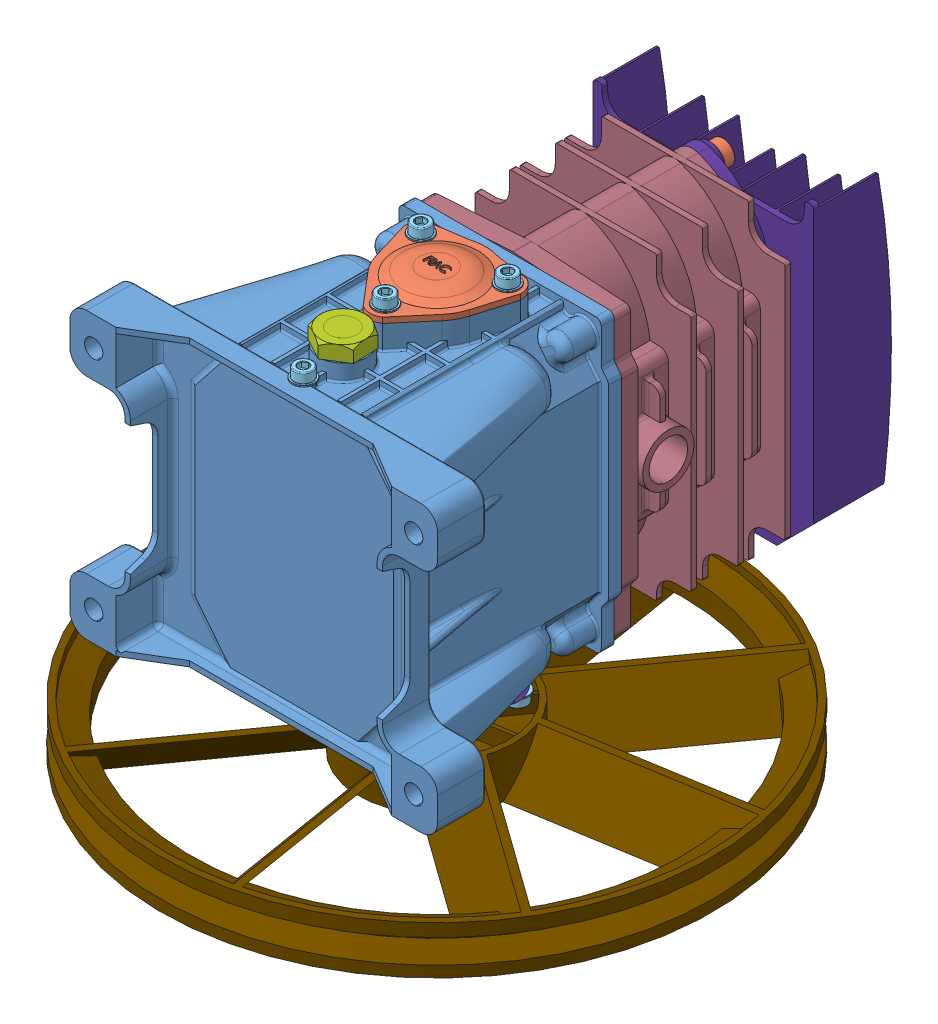
SolidWorks assembly ASSIEME, configuration Default. Lengths in mm.
Overall size (344.78 250.04 359.67).
63 component instances, 27 part files, 88 mates.
Components (placement in the parent):
- carter-1: carter [Default] at (-13.0886 -2.2266 200) size (200 182 141)
- COPERCHIO_6203-1: COPERCHIO_6203 [Default] at (-13.0886 84.7734 200) x (1 0 0) z (0 1 0) size (63.63 62.78 24)
- SKF_6203-1: SKF_6203 [Default] at (-13.0886 80.7734 123.5) x (0 -1 0) z (-0.202548 0 -0.979272) size (12 40 40)
  - SKF_6203_12-1: SKF_6203_12 [Default] x (1 0 0) z (0 -0.707107 0.707107) size (6.75 6.75 6.75)
  - SKF_6203_12-2: SKF_6203_12 [Default] x (1 0 0) z (0 -1 0) size (6.75 6.75 6.75)
  - SKF_6203_12-3: SKF_6203_12 [Default] x (1 0 0) z (0 -0.707107 -0.707107) size (6.75 6.75 6.75)
  - SKF_6203_12-4: SKF_6203_12 [Default] x (1 0 0) z (0 0 -1) size (6.75 6.75 6.75)
  - SKF_6203_12-5: SKF_6203_12 [Default] x (1 0 0) z (0 0.707107 -0.707107) size (6.75 6.75 6.75)
  - SKF_6203_12-6: SKF_6203_12 [Default] x (1 0 0) z (0 1 0) size (6.75 6.75 6.75)
  - SKF_6203_12-7: SKF_6203_12 [Default] x (1 0 0) z (0 0.707107 0.707107) size (6.75 6.75 6.75)
  - SKF_6203_12-8: SKF_6203_12 [Default] at origin size (6.75 6.75 6.75)
  - SKF_6203_21-1: SKF_6203_21 [Default] at origin size (12 40 40)
  - SKF_6203_23-1: SKF_6203_23 [Default] at origin size (12 24.5 24.5)
- albero (2)-2: albero (2) [Default] at (-13.0886 -75.1766 123.5) x (-0.16255 0 -0.9867) z (0 -1 0) size (47.4 88.29 224.6)
- boccola-1: boccola [Default] at (-13.0886 67.7734 123.5) x (-0.874312 0 0.485365) z (0 1 0) size (21 21 1)
- COPERCHIO_6204-1: COPERCHIO_6204 [Default] at (-15.8848 -102.2266 135.5048) x (-1 0 0) z (0 1 0) size (66.44 64.43 29)
- SKF_6204-1: SKF_6204 [Default] at (-13.0886 -89.1766 123.5) x (0 1 0) z (-0.972829 0 0.231526) size (14 47 47)
  - SKF_6204_12-1: SKF_6204_12 [Default] x (1 0 0) z (0 -0.707107 0.707107) size (7.94 7.94 7.94)
  - SKF_6204_12-2: SKF_6204_12 [Default] x (1 0 0) z (0 -1 0) size (7.94 7.94 7.94)
  - SKF_6204_12-3: SKF_6204_12 [Default] x (1 0 0) z (0 -0.707107 -0.707107) size (7.94 7.94 7.94)
  - SKF_6204_12-4: SKF_6204_12 [Default] x (1 0 0) z (0 0 -1) size (7.94 7.94 7.94)
  - SKF_6204_12-5: SKF_6204_12 [Default] x (1 0 0) z (0 0.707107 -0.707107) size (7.94 7.94 7.94)
  - SKF_6204_12-6: SKF_6204_12 [Default] x (1 0 0) z (0 1 0) size (7.94 7.94 7.94)
  - SKF_6204_12-7: SKF_6204_12 [Default] x (1 0 0) z (0 0.707107 0.707107) size (7.94 7.94 7.94)
  - SKF_6204_12-8: SKF_6204_12 [Default] at origin size (7.94 7.94 7.94)
  - SKF_6204_21-1: SKF_6204_21 [Default] at origin size (14 47 47)
  - SKF_6204_23-1: SKF_6204_23 [Default] at origin size (14 28.8 28.8)
- SKF_20X47X7_CRW1_R-1: SKF_20X47X7_CRW1_R [Default] at (-13.0886 -97.2266 123.5) x (0 1 0) z (0.036674 0 -0.999327) size (7 47 47)
- cilindro-1: cilindro [Default] at (-13.0886 -2.2266 82) x (0 1 0) z (0 0 1) size (170 120 97.5)
- biella (1)-1: biella (1) [Default] at (-33.8093 30.3234 126.9135) x (-0.243773 0 0.969832) z (0 1 0) size (142 47 15.03)
- biella (1)-2: biella (1) [Default] at (7.6321 -34.6766 120.0865) x (0.243773 0 0.969832) z (0 1 0) size (142 47 15.03)
- spinotto-1: spinotto [Default] at (-13.0886 53.5234 44.4778) x (0.997872 0 0.065206) z (0 -1 0) size (13 13 46.5)
- spinotto-2: spinotto [Default] at (-13.0886 -11.4766 37.6507) x (0.995135 0 0.098522) z (0 -1 0) size (13 13 46.5)
- Pistone_Compressore (1)-1: Pistone_Compressore (1) [Default] at (-13.0886 30.2734 66.4778) x (0 0 -1) z (0 -1 0) size (47 53 53)
- Pistone_Compressore (1)-2: Pistone_Compressore (1) [Default] at (-13.0886 -34.7266 59.6507) x (0 0 -1) z (0 -1 0) size (47 53 53)
- testata-1: testata [Default] at (-13.0886 -2.2266 -21.5) x (0 -1 0) z (0 0 1) size (170 120 48.28)
- puleggia2-1: puleggia2 [Default] at (-161.0937 -111.4306 147.8824) x (0 -1 0) z (-0.16255 0 -0.9867) size (36.2 300 300)
- chiavetta-1: chiavetta [Default] at (-0.5703 -123.1766 119.5121) x (-0.041845 -0.9991 0.006894) z (0.16255 0 0.9867) size (15.94 7.3 3.9)
- Bulloni a brugola M8x35mm-1: Bulloni a brugola M8x35mm [Default] at (-13.0886 67.7734 10.5) x (0.984599 -0.17483 0) z (0 0 -1) size (16 16 43.35)
- Bulloni a brugola M8x45mm-1: Bulloni a brugola M8x45mm [Default] at (-50.5886 26.2734 7.5) x (-0.918061 -0.396439 0) z (0 0 -1) size (16 16 53.35)
- Bulloni a brugola M8x45mm-2: Bulloni a brugola M8x45mm [Default] at (24.4114 26.2734 20.5) x (-0.229828 0.973231 0) z (0 0 -1) size (16 16 53.35)
- Bulloni a brugola M8x45mm-3: Bulloni a brugola M8x45mm [Default] at (24.4114 -30.7266 20.5) x (-0.229828 0.973231 0) z (0 0 -1) size (16 16 53.35)
- Bulloni a brugola M8x45mm-4: Bulloni a brugola M8x45mm [Default] at (-13.0886 -72.2266 7.5) x (-0.461564 -0.887107 0) z (0 0 -1) size (16 16 53.35)
- Bulloni a brugola M8x45mm-5: Bulloni a brugola M8x45mm [Default] at (-50.5886 -30.7266 7.5) x (-0.618825 0.785529 0) z (0 0 -1) size (16 16 53.35)
- Bulloni a brugola M8x15-1: Bulloni a brugola M8x15 [Default] at (-13.0886 -127.6306 123.5) x (0.472726 0 0.88121) z (0 -1 0) size (24 24 28.35)
- Bulloni a brugola M6x6mm-1: Bulloni a brugola M6x6mm [Default] at (-13.0886 73.7734 151.5) x (0.218907 0 0.975746) z (0 1 0) size (12 12 20.29)
- Bulloni a brugola M6x6mm-2: Bulloni a brugola M6x6mm [Default] at (-36.7318 73.7734 108.5) x (-1 0 0) z (0 1 0) size (12 12 20.29)
- Bulloni a brugola M6x6mm-3: Bulloni a brugola M6x6mm [Default] at (10.5546 73.7734 108.5) x (-1 0 0) z (0 1 0) size (12 12 20.29)
- Bulloni a brugola M6x6mm-7: Bulloni a brugola M6x6mm [Default] at (14.0223 -88.2266 106.5) x (0 0 1) z (0 -1 0) size (12 12 20.29)
- Bulloni a brugola M6x6mm-8: Bulloni a brugola M6x6mm [Default] at (-40.1995 -88.2266 106.5) x (0 0 1) z (0 -1 0) size (12 12 20.29)
- Bulloni a brugola M6x6mm-9: Bulloni a brugola M6x6mm [Default] at (-13.0886 -88.2266 155.5) x (0 0 1) z (0 -1 0) size (12 12 20.29)
- Bulloni a brugola M6x6mm-11: Bulloni a brugola M6x6mm [Default] at (-13.0886 61.2734 196) x (0 0 -1) z (0 1 0) size (12 12 20.29)
- 7941013-2: 7941013 [Default] at (-13.0886 54.5234 44.4778) x (0 -1 0) z (0 0 1) size (1 13.87 14.1)
- 7941013-3: 7941013 [Default] at (-13.0886 7.0234 44.4778) x (0 -1 0) z (0 0 1) size (1 13.87 14.1)
- 7941013-4: 7941013 [Default] at (-13.0886 -11.4766 37.6507) x (0 1 0) z (0 0 1) size (1 13.87 14.1)
- 7941013-5: 7941013 [Default] at (-13.0886 -58.9766 37.6507) x (0 1 0) z (0 0 1) size (1 13.87 14.1)
- tappo livello olio-1: tappo livello olio [Default] at (-13.0886 67.7734 174.5) x (-0.88085 0 -0.473395) z (0 1 0) size (27.71 24 21)
- segmento1-1: segmento1 [Default] at (-13.0886 30.2734 23.4778) size (55 54.99 2)
- segmento1-2: segmento1 [Default] at (-13.0886 -34.7266 16.6507) size (55 54.99 2)
- segmento1-3: segmento1 [Default] at (-13.0886 30.2734 27.4778) x (0 -1 0) z (0 0 1) size (55 54.99 2)
- segmento1-4: segmento1 [Default] at (-13.0886 -34.7266 20.6507) x (0 -1 0) z (0 0 1) size (55 54.99 2)
- raschia_olio-2: raschia_olio [Default] at (-13.0886 30.2734 31.4778) x (0 1 0) z (0 0 1) size (55 55 3)
- raschia_olio-3: raschia_olio [Default] at (-13.0886 -34.7266 24.6507) x (-1 0 0) z (0 0 1) size (55 55 3)
Mates (geometry in assembly coordinates):
- Concentrico1: concentric aligned: cylinder of carter-1 through (-13.0886 -149.8662 123.5) axis (0 1 0) radius 22.5; cylinder of COPERCHIO_6203-1 through (-13.0886 68.7734 123.5) axis (0 1 0) radius 22.5
- Coincidente1: coincident anti-aligned: plane of carter-1 through (-13.0886 84.7734 123.5) normal (0 1 0); plane of COPERCHIO_6203-1 through (-35.4014 84.7734 109.4469) normal (0 -1 0)
- Concentrico2: concentric anti-aligned: cylinder of COPERCHIO_6203-1 through (-13.0886 68.7734 123.5) axis (0 1 0) radius 20; cylinder of SKF_6203-1/SKF_6203_21-1 through (-13.0886 30.7734 123.5) axis (0 -1 0) radius 20
- Coincidente2: coincident anti-aligned: plane of COPERCHIO_6203-1 through (-13.0886 80.7734 123.5) normal (0 -1 0); plane of SKF_6203-1/SKF_6203_21-1 through (-32.0865 80.7734 127.4294) normal (0 1 0)
- Coincidente3: coincident anti-aligned: plane of albero (2)-2 through (-19.0088 67.7734 124.4753) normal (0 1 0); plane of boccola-1 through (-13.0886 67.7734 123.5) normal (0 -1 0)
- Concentrico5: concentric anti-aligned: cylinder of SKF_6203-1/SKF_6203_23-1 through (-13.0886 -19.2266 123.5) axis (0 -1 0) radius 8.5; cylinder of albero (2)-2 through (-13.0886 67.7734 123.5) axis (0 1 0) radius 8.5
- Coincidente5: coincident anti-aligned: plane of SKF_6203-1/SKF_6203_23-1 through (-22 68.7734 125.3432) normal (0 -1 0); plane of boccola-1 through (-13.0886 68.7734 123.5) normal (0 1 0)
- Coincidente6: coincident anti-aligned: plane of albero (2)-2 through (-19.0088 67.7734 124.4753) normal (0 1 0); plane of boccola-1 through (-13.0886 67.7734 123.5) normal (0 -1 0)
- Concentrico6: concentric anti-aligned: cylinder of albero (2)-2 through (-13.0886 67.7734 123.5) axis (0 1 0) radius 8.5; cylinder of boccola-1 through (-13.0886 68.7734 123.5) axis (0 -1 0) radius 10.5
- Concentrico7: concentric aligned: cylinder of carter-1 through (-13.0886 -63.2266 123.5) axis (0 -1 0) radius 26.5; cylinder of COPERCHIO_6204-1 through (-13.0886 -73.2266 123.5) axis (0 -1 0) radius 26.5
- Coincidente7: coincident anti-aligned: plane of carter-1 through (-13.0886 -97.2266 123.5) normal (0 -1 0); plane of COPERCHIO_6204-1 through (-13.0886 -97.2266 123.5) normal (0 1 0)
- Concentrico8: concentric anti-aligned: cylinder of COPERCHIO_6204-1 through (-13.0886 -73.2266 123.5) axis (0 -1 0) radius 23.5; cylinder of SKF_6204-1/SKF_6204_21-1 through (-13.0886 -39.1766 123.5) axis (0 1 0) radius 23.5
- Concentrico9: concentric anti-aligned: cylinder of albero (2)-2 through (-13.0886 -75.1766 123.5) axis (0 -1 0) radius 10; cylinder of SKF_6204-1/SKF_6204_23-1 through (-13.0886 10.8234 123.5) axis (0 1 0) radius 10
- Coincidente8: coincident anti-aligned: plane of albero (2)-2 through (-13.0886 -75.1766 123.5) normal (0 -1 0); plane of SKF_6204-1/SKF_6204_23-1 through (-15.6354 -75.1766 112.7989) normal (0 1 0)
- Concentrico10: concentric anti-aligned: cylinder of COPERCHIO_6204-1 through (-13.0886 -73.2266 123.5) axis (0 -1 0) radius 23.5; cylinder of SKF_20X47X7_CRW1_R-1 through (-13.0886 -47.2266 123.5) axis (0 1 0) radius 23.5
- Coincidente9: coincident anti-aligned: plane of COPERCHIO_6204-1 through (-13.0886 -97.2266 123.5) normal (0 1 0); plane of SKF_20X47X7_CRW1_R-1 through (9.0465 -97.2266 124.3123) normal (0 -1 0)
- Concentrico11: concentric anti-aligned: cylinder of carter-1 through (32.9114 66.7734 82) axis (0 0 -1) radius 3.5; cylinder of cilindro-1 through (32.9114 66.7734 72) axis (0 0 1) radius 4
- Concentrico12: concentric anti-aligned: cylinder of carter-1 through (-59.0886 -71.2266 82) axis (0 0 -1) radius 3.5; cylinder of cilindro-1 through (-59.0886 -71.2266 72) axis (0 0 1) radius 4
- Coincidente10: coincident anti-aligned: plane of carter-1 through (-13.0886 -2.2266 82) normal (0 0 -1); plane of cilindro-1 through (-13.0886 -79.2203 82) normal (0 0 1)
- Concentrico15: concentric aligned: cylinder of cilindro-1 through (-13.0886 30.2734 72) axis (0 0 1) radius 27.5; cylinder of Pistone_Compressore (1)-1 through (-13.0886 30.2734 117.5487) axis (0 0 1) radius 26.5
- Concentrico16: concentric aligned: cylinder of cilindro-1 through (-13.0886 -34.7266 72) axis (0 0 1) radius 27.5; cylinder of Pistone_Compressore (1)-2 through (-13.0886 -34.7266 110.7216) axis (0 0 1) radius 26.5
- Concentrico17: concentric anti-aligned: cylinder of spinotto-2 through (-13.0886 -57.9766 37.6507) axis (0 1 0) radius 6.5; cylinder of Pistone_Compressore (1)-2 through (-13.0886 -8.2266 37.6507) axis (0 -1 0) radius 6.5
- Concentrico18: concentric anti-aligned: cylinder of spinotto-1 through (-13.0886 7.0234 44.4778) axis (0 1 0) radius 6.5; cylinder of Pistone_Compressore (1)-1 through (-13.0886 56.7734 44.4778) axis (0 -1 0) radius 6.5
- Coincidente11: coincident aligned: plane of spinotto-1 through (-13.0886 7.0234 44.4778) normal (0 -1 0); plane of Pistone_Compressore (1)-1 through (-13.0886 7.0234 44.4778) normal (0 -1 0)
- Coincidente12: coincident aligned: plane of spinotto-2 through (-13.0886 -11.4766 37.6507) normal (0 1 0); plane of Pistone_Compressore (1)-2 through (-13.0886 -11.4766 37.6507) normal (0 1 0)
- Concentrico20: concentric anti-aligned: cylinder of biella (1)-1 through (-13.0886 37.8234 44.4778) axis (0 -1 0) radius 6.5; cylinder of spinotto-1 through (-13.0886 7.0234 44.4778) axis (0 1 0) radius 6.5
- Concentrico21: concentric anti-aligned: cylinder of biella (1)-2 through (-13.0886 -27.1766 37.6507) axis (0 -1 0) radius 6.5; cylinder of spinotto-2 through (-13.0886 -57.9766 37.6507) axis (0 1 0) radius 6.5
- Concentrico22: concentric anti-aligned: cylinder of albero (2)-2 through (-33.8093 22.8234 126.9135) axis (0 1 0) radius 17.5; cylinder of biella (1)-1 through (-33.8093 37.8234 126.9135) axis (0 -1 0) radius 17.5
- Concentrico23: concentric aligned: cylinder of albero (2)-2 through (7.6321 -27.1766 120.0865) axis (0 -1 0) radius 17.5; cylinder of biella (1)-2 through (7.6321 -27.1766 120.0865) axis (0 -1 0) radius 17.5
- Coincidente14: coincident anti-aligned: plane of albero (2)-2 through (7.6321 -27.1766 120.0865) normal (0 -1 0); plane of biella (1)-2 through (7.6321 -27.1766 120.0865) normal (0 1 0)
- Coincidente15: coincident anti-aligned: plane of albero (2)-2 through (-33.8093 22.8234 126.9135) normal (0 1 0); plane of biella (1)-1 through (-33.8093 22.8234 126.9135) normal (0 -1 0)
- Concentrico27: concentric aligned: cylinder of cilindro-1 through (-13.0886 67.7734 -15.5) axis (0 0 -1) radius 3.4; cylinder of testata-1 through (-13.0886 67.7734 -21.5) axis (0 0 -1) radius 4
- Concentrico28: concentric aligned: cylinder of cilindro-1 through (-13.0886 -72.2266 -15.5) axis (0 0 -1) radius 3.4; cylinder of testata-1 through (-13.0886 -72.2266 -21.5) axis (0 0 -1) radius 4
- Coincidente17: coincident anti-aligned: plane of cilindro-1 through (-13.0886 -2.2266 -15.5) normal (0 0 -1); plane of testata-1 through (-54.5886 30.2734 -15.5) normal (0 0 1)
- Concentrico34: concentric aligned: cylinder of albero (2)-2 through (0.0636 -123.1766 123.3603) axis (-0.16255 0 -0.9867) radius 8; cylinder of chiavetta-1 through (0.0636 -123.1766 123.3603) axis (-0.16255 0 -0.9867) radius 8
- Coincidente20: coincident anti-aligned: plane of albero (2)-2 through (0.0636 -123.1766 123.3603) normal (-0.16255 0 -0.9867); plane of chiavetta-1 through (0.0636 -123.1766 123.3603) normal (0.16255 0 0.9867)
- Concentrico36: concentric aligned: circle of albero (2)-2; circle of puleggia2-1
- Coincidente31: coincident anti-aligned: plane of puleggia2-1 through (-0.7498 -118.3286 121.4673) normal (-0.985813 0.042409 0.162403); plane of chiavetta-1 through (-1.2604 -123.1469 119.6258) normal (0.985813 -0.042409 -0.162403)
- Vite1: screw = 1 anti-aligned: cylinder of cilindro-1 through (-13.0886 67.7734 -15.5) axis (0 0 -1) radius 3.4; cylinder of Bulloni a brugola M8x35mm-1 through (-13.0886 67.7734 -24.5) axis (0 0 1) radius 4
- Coincidente32: coincident anti-aligned: plane of testata-1 through (-58.0886 72.7734 -24.5) normal (0 0 -1); plane of Bulloni a brugola M8x35mm-1 through (-13.0886 67.7734 -24.5) normal (0 0 1)
- Vite2: screw = 1 anti-aligned: cylinder of cilindro-1 through (-50.5886 26.2734 -15.5) axis (0 0 -1) radius 3.4; cylinder of Bulloni a brugola M8x45mm-1 through (-50.5886 26.2734 -37.5) axis (0 0 1) radius 4
- Coincidente33: coincident anti-aligned: plane of testata-1 through (-50.5886 26.2734 -37.5) normal (0 0 -1); plane of Bulloni a brugola M8x45mm-1 through (-50.5886 26.2734 -37.5) normal (0 0 1)
- Vite3: screw = 1 anti-aligned: cylinder of cilindro-1 through (24.4114 26.2734 -15.5) axis (0 0 -1) radius 3.4; cylinder of Bulloni a brugola M8x45mm-2 through (24.4114 26.2734 -24.5) axis (0 0 1) radius 4
- Vite4: screw = 1 anti-aligned: cylinder of cilindro-1 through (24.4114 -30.7266 -15.5) axis (0 0 -1) radius 3.4; cylinder of Bulloni a brugola M8x45mm-3 through (24.4114 -30.7266 -24.5) axis (0 0 1) radius 4
- Vite5: screw = 1 anti-aligned: cylinder of cilindro-1 through (-13.0886 -72.2266 -15.5) axis (0 0 -1) radius 3.4; cylinder of Bulloni a brugola M8x45mm-4 through (-13.0886 -72.2266 -37.5) axis (0 0 1) radius 4
- Vite6: screw = 1 anti-aligned: cylinder of cilindro-1 through (-50.5886 -30.7266 -15.5) axis (0 0 -1) radius 3.4; cylinder of Bulloni a brugola M8x45mm-5 through (-50.5886 -30.7266 -37.5) axis (0 0 1) radius 4
- Coincidente34: coincident anti-aligned: plane of testata-1 through (-50.5886 -30.7266 -37.5) normal (0 0 -1); plane of Bulloni a brugola M8x45mm-5 through (-50.5886 -30.7266 -37.5) normal (0 0 1)
- Coincidente35: coincident anti-aligned: plane of testata-1 through (-13.0886 -72.2266 -37.5) normal (0 0 -1); plane of Bulloni a brugola M8x45mm-4 through (-13.0886 -72.2266 -37.5) normal (0 0 1)
- Coincidente37: coincident anti-aligned: plane of testata-1 through (-58.0886 72.7734 -24.5) normal (0 0 -1); plane of Bulloni a brugola M8x45mm-3 through (24.4114 -30.7266 -24.5) normal (0 0 1)
- Coincidente38: coincident anti-aligned: plane of testata-1 through (-58.0886 72.7734 -24.5) normal (0 0 -1); plane of Bulloni a brugola M8x45mm-2 through (24.4114 26.2734 -24.5) normal (0 0 1)
- Vite8: screw = 1 anti-aligned: cylinder of albero (2)-2 through (-13.0886 -144.1766 123.5) axis (0 -1 0) radius 3.4; cylinder of Bulloni a brugola M8x15-1 through (-13.0886 -147.6306 123.5) axis (0 1 0) radius 4
- Coincidente39: coincident anti-aligned: plane of puleggia2-1 through (-13.0886 -147.6306 123.5) normal (0 -1 0); plane of Bulloni a brugola M8x15-1 through (-13.0886 -147.6306 123.5) normal (0 1 0)
- Vite11: screw = 1 anti-aligned: cylinder of carter-1 through (-36.7318 72.7734 108.5) axis (0 1 0) radius 2.5; cylinder of Bulloni a brugola M6x6mm-2 through (-36.7318 87.7734 108.5) axis (0 -1 0) radius 3
- Vite12: screw = 1 anti-aligned: cylinder of carter-1 through (10.5546 72.7734 108.5) axis (0 1 0) radius 2.5; cylinder of Bulloni a brugola M6x6mm-3 through (10.5546 87.7734 108.5) axis (0 -1 0) radius 3
- Vite13: screw = 1 anti-aligned: cylinder of carter-1 through (-13.0886 72.7734 151.5) axis (0 1 0) radius 2.5; cylinder of Bulloni a brugola M6x6mm-1 through (-13.0886 87.7734 151.5) axis (0 -1 0) radius 3
- Coincidente40: coincident anti-aligned: plane of COPERCHIO_6203-1 through (-35.4014 87.7734 109.4469) normal (0 1 0); plane of Bulloni a brugola M6x6mm-1 through (-13.0886 87.7734 151.5) normal (0 -1 0)
- Coincidente41: coincident anti-aligned: plane of COPERCHIO_6203-1 through (-35.4014 87.7734 109.4469) normal (0 1 0); plane of Bulloni a brugola M6x6mm-3 through (10.5546 87.7734 108.5) normal (0 -1 0)
- Coincidente42: coincident anti-aligned: plane of COPERCHIO_6203-1 through (-35.4014 87.7734 109.4469) normal (0 1 0); plane of Bulloni a brugola M6x6mm-2 through (-36.7318 87.7734 108.5) normal (0 -1 0)
- Vite14: screw = 1 anti-aligned: cylinder of carter-1 through (14.0223 -27.4455 106.5) axis (0 -1 0) radius 2.5; cylinder of Bulloni a brugola M6x6mm-7 through (14.0223 -102.2266 106.5) axis (0 1 0) radius 3
- Vite15: screw = 1 anti-aligned: cylinder of carter-1 through (-40.1995 -27.4455 106.5) axis (0 -1 0) radius 2.5; cylinder of Bulloni a brugola M6x6mm-8 through (-40.1995 -102.2266 106.5) axis (0 1 0) radius 3
- Vite16: screw = 1 anti-aligned: cylinder of carter-1 through (-13.0886 -27.4455 155.5) axis (0 -1 0) radius 2.5; cylinder of Bulloni a brugola M6x6mm-9 through (-13.0886 -102.2266 155.5) axis (0 1 0) radius 3
- Coincidente43: coincident anti-aligned: plane of COPERCHIO_6204-1 through (-13.0886 -102.2266 123.5) normal (0 -1 0); plane of Bulloni a brugola M6x6mm-9 through (-13.0886 -102.2266 155.5) normal (0 1 0)
- Coincidente44: coincident anti-aligned: plane of COPERCHIO_6204-1 through (-13.0886 -102.2266 123.5) normal (0 -1 0); plane of Bulloni a brugola M6x6mm-7 through (14.0223 -102.2266 106.5) normal (0 1 0)
- Coincidente45: coincident anti-aligned: plane of COPERCHIO_6204-1 through (-13.0886 -102.2266 123.5) normal (0 -1 0); plane of Bulloni a brugola M6x6mm-8 through (-40.1995 -102.2266 106.5) normal (0 1 0)
- Vite17: screw = 1 anti-aligned: cylinder of carter-1 through (-13.0886 75.2734 196) axis (0 1 0) radius 2.5; cylinder of Bulloni a brugola M6x6mm-11 through (-13.0886 75.2734 196) axis (0 -1 0) radius 3
- Coincidente46: coincident anti-aligned: plane of carter-1 through (-103.9768 75.2734 223) normal (0 1 0); plane of Bulloni a brugola M6x6mm-11 through (-13.0886 75.2734 196) normal (0 -1 0)
- Concentrico45: concentric aligned: cylinder of Pistone_Compressore (1)-1 through (-13.0886 53.5234 44.4778) axis (0 1 0) radius 7.05; cylinder of 7941013-2 through (-13.0886 53.5234 44.4778) axis (0 1 0) radius 7.05
- Coincidente48: coincident anti-aligned: plane of Pistone_Compressore (1)-1 through (-13.0886 53.5234 44.4778) normal (0 1 0); plane of 7941013-2 through (-13.0886 53.5234 44.4778) normal (0 -1 0)
- Concentrico46: concentric anti-aligned: cylinder of Pistone_Compressore (1)-1 through (-13.0886 7.0234 44.4778) axis (0 -1 0) radius 7.05; cylinder of 7941013-3 through (-13.0886 6.0234 44.4778) axis (0 1 0) radius 7.05
- Coincidente49: coincident anti-aligned: plane of Pistone_Compressore (1)-1 through (-13.0886 7.0234 44.4778) normal (0 -1 0); plane of 7941013-3 through (-13.0886 7.0234 44.4778) normal (0 1 0)
- Concentrico47: concentric anti-aligned: cylinder of Pistone_Compressore (1)-2 through (-13.0886 -11.4766 37.6507) axis (0 1 0) radius 7.05; cylinder of 7941013-4 through (-13.0886 -10.4766 37.6507) axis (0 -1 0) radius 7.05
- Coincidente50: coincident anti-aligned: plane of Pistone_Compressore (1)-2 through (-13.0886 -11.4766 37.6507) normal (0 1 0); plane of 7941013-4 through (-13.0886 -11.4766 37.6507) normal (0 -1 0)
- Concentrico48: concentric aligned: cylinder of Pistone_Compressore (1)-2 through (-13.0886 -57.9766 37.6507) axis (0 -1 0) radius 7.05; cylinder of 7941013-5 through (-13.0886 -57.9766 37.6507) axis (0 -1 0) radius 7.05
- Coincidente51: coincident anti-aligned: plane of Pistone_Compressore (1)-2 through (-13.0886 -57.9766 37.6507) normal (0 -1 0); plane of 7941013-5 through (-13.0886 -57.9766 37.6507) normal (0 1 0)
- Vite18: screw = 1 anti-aligned: cylinder of carter-1 through (-13.0886 80.7734 174.5) axis (0 1 0) radius 10.25; cylinder of tappo livello olio-1 through (-13.0886 80.7734 174.5) axis (0 -1 0) radius 10
- Coincidente52: coincident anti-aligned: plane of carter-1 through (-13.0886 80.7734 174.5) normal (0 1 0); plane of tappo livello olio-1 through (-13.0886 80.7734 174.5) normal (0 -1 0)
- Concentrico49: concentric anti-aligned: cylinder of Pistone_Compressore (1)-1 through (-13.0886 30.2734 66.4778) axis (0 0 1) radius 23.5; cylinder of segmento1-1 through (-13.0886 30.2734 25.4778) axis (0 0 -1) radius 23.5
- Coincidente53: coincident anti-aligned: plane of Pistone_Compressore (1)-1 through (-13.0886 3.7734 23.4778) normal (0 0 1); plane of segmento1-1 through (-15.7938 54.6236 23.4778) normal (0 0 -1)
- Concentrico50: concentric anti-aligned: cylinder of Pistone_Compressore (1)-2 through (-13.0886 -34.7266 59.6507) axis (0 0 1) radius 23.5; cylinder of segmento1-2 through (-13.0886 -34.7266 18.6507) axis (0 0 -1) radius 23.5
- Coincidente54: coincident anti-aligned: plane of Pistone_Compressore (1)-2 through (-13.0886 -61.2266 16.6507) normal (0 0 1); plane of segmento1-2 through (-15.7938 -10.3764 16.6507) normal (0 0 -1)
- Concentrico51: concentric anti-aligned: cylinder of Pistone_Compressore (1)-1 through (-13.0886 30.2734 66.4778) axis (0 0 1) radius 23.5; cylinder of segmento1-3 through (-13.0886 30.2734 29.4778) axis (0 0 -1) radius 23.5
- Coincidente55: coincident anti-aligned: plane of Pistone_Compressore (1)-1 through (-13.0886 3.7734 27.4778) normal (0 0 1); plane of segmento1-3 through (11.2616 32.9786 27.4778) normal (0 0 -1)
- Concentrico52: concentric anti-aligned: cylinder of Pistone_Compressore (1)-2 through (-13.0886 -34.7266 59.6507) axis (0 0 1) radius 23.5; cylinder of segmento1-4 through (-13.0886 -34.7266 22.6507) axis (0 0 -1) radius 23.5
- Coincidente56: coincident anti-aligned: plane of Pistone_Compressore (1)-2 through (-13.0886 -61.2266 20.6507) normal (0 0 1); plane of segmento1-4 through (11.2616 -32.0214 20.6507) normal (0 0 -1)
- Concentrico53: concentric anti-aligned: cylinder of Pistone_Compressore (1)-1 through (-13.0886 30.2734 66.4778) axis (0 0 1) radius 23; cylinder of raschia_olio-2 through (-13.0886 30.2734 34.4778) axis (0 0 -1) radius 23
- Coincidente57: coincident anti-aligned: plane of Pistone_Compressore (1)-1 through (-13.0886 7.2734 31.4778) normal (0 0 1); plane of raschia_olio-2 through (-36.9396 27.6031 31.4778) normal (0 0 -1)
- Concentrico54: concentric anti-aligned: cylinder of Pistone_Compressore (1)-2 through (-13.0886 -34.7266 59.6507) axis (0 0 1) radius 23; cylinder of raschia_olio-3 through (-13.0886 -34.7266 27.6507) axis (0 0 -1) radius 23
- Coincidente58: coincident anti-aligned: plane of Pistone_Compressore (1)-2 through (-13.0886 -57.7266 24.6507) normal (0 0 1); plane of raschia_olio-3 through (-10.4183 -58.5776 24.6507) normal (0 0 -1)
